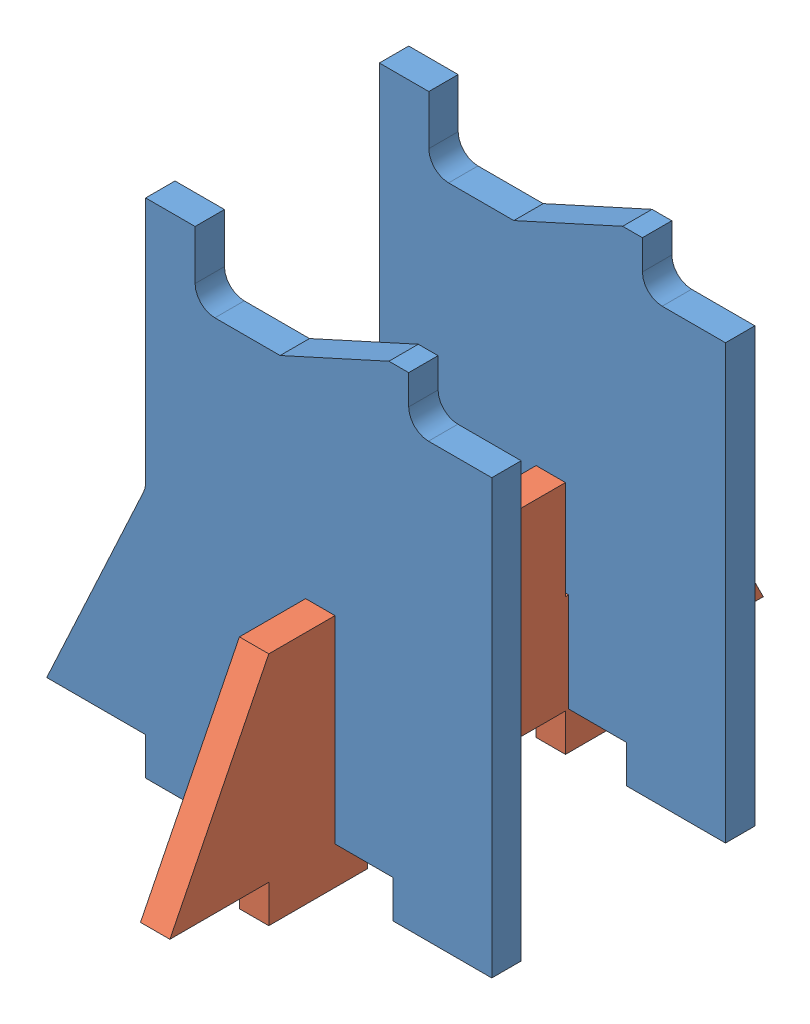
SolidWorks assembly PhoneHolderAssembly, configuration Default. Lengths in mm.
Overall size (45 50.81 60).
3 component instances, 2 part files, 7 mates.
Components (placement in the parent):
- Phone holder-1: Phone holder [Default] at (10.7576 25.1394 44.3363) size (45 50.81 2.97)
- holdertriangle-1: holdertriangle [Default] at (9.4368 15.1394 57.6383) x (0 0 -1) z (1 0 0) size (60 23.81 2.97)
- Phone holder-2: Phone holder [Default] at (10.7576 25.1394 67.9685) size (45 50.81 2.97)
Mates (geometry in assembly coordinates):
- Coincident1: coincident anti-aligned: plane of Phone holder-1 through (9.1066 15.1394 44.3363) normal (0 -1 0); plane of holdertriangle-1 through (9.4368 15.1394 70.9403) normal (0 1 0)
- Parallel1: parallel aligned: plane of Phone holder-1 through (-6.7424 5.1394 47.3081) normal (-1 0 0); plane of holdertriangle-1 through (9.4368 15.1394 57.6383) normal (-1 0 0)
- Coincident3: coincident anti-aligned: plane of Phone holder-1 through (10.7576 25.1394 44.3363) normal (0 0 -1); plane of holdertriangle-1 through (9.4368 35.1394 44.3363) normal (0 0 1)
- Coincident4: coincident anti-aligned: plane of Phone holder-1 through (12.4086 5.1394 44.3363) normal (-1 0 0); plane of holdertriangle-1 through (12.4086 15.1394 57.6383) normal (1 0 0)
- Coincident5: coincident anti-aligned: plane of holdertriangle-1 through (9.4368 15.1394 70.9403) normal (0 1 0); plane of Phone holder-2 through (9.1066 15.1394 67.9685) normal (0 -1 0)
- Coincident6: coincident anti-aligned: plane of holdertriangle-1 through (9.4368 35.1394 70.9403) normal (0 0 -1); plane of Phone holder-2 through (10.7576 25.1394 70.9403) normal (0 0 1)
- Coincident7: coincident anti-aligned: plane of holdertriangle-1 through (12.4086 15.1394 57.6383) normal (1 0 0); plane of Phone holder-2 through (12.4086 5.1394 67.9685) normal (-1 0 0)
